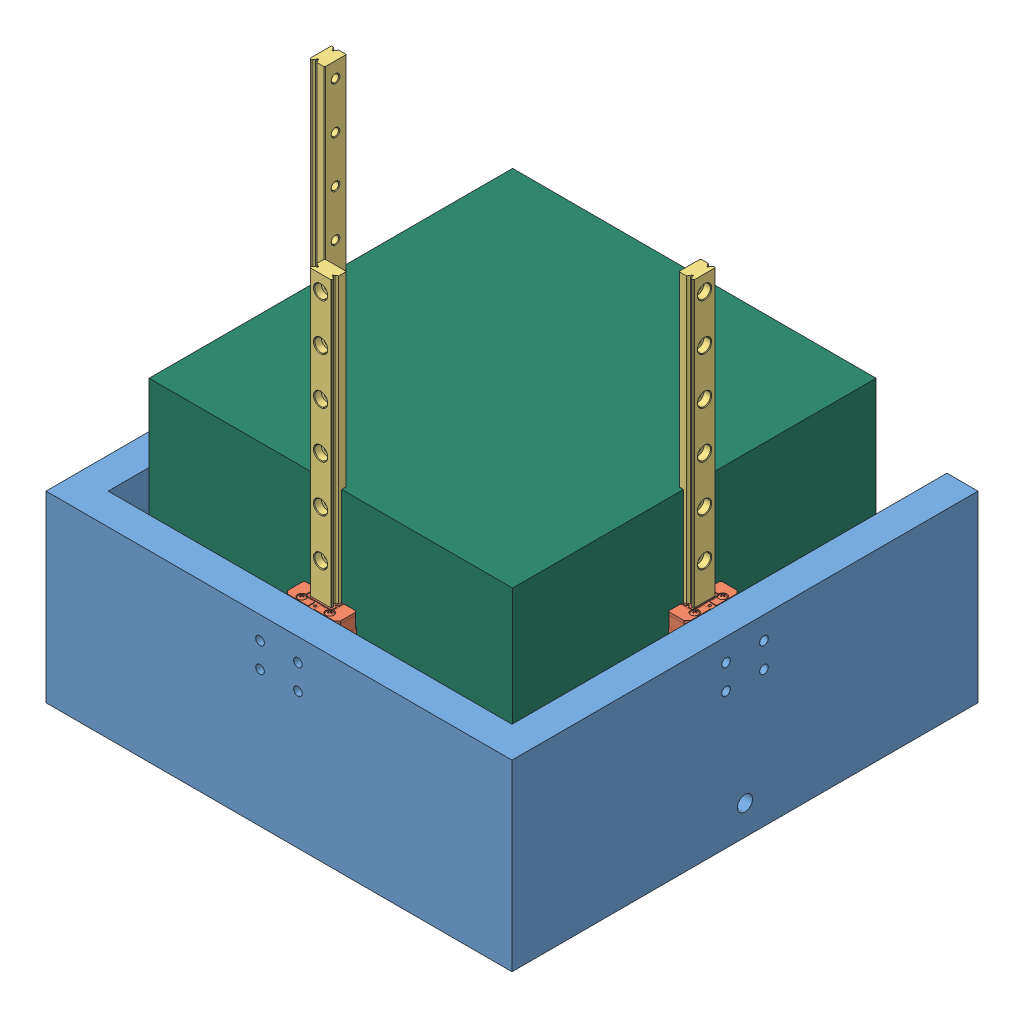
SolidWorks assembly faul_mntg_rig_assem, configuration Default. Lengths in mm.
Overall size (150 150.47 150).
44 component instances, 18 part files, 26 mates.
Components (placement in the parent):
- rails-1: rails [Default] at (23.4642 89.2869 124.8226) size (150 59 150)
- MGN7C-1: MGN7C [MGN7C] at (23.5642 78.0369 186.5726) x (1 0 0) z (0 -1 0) size (17 6.5 23.31)
- MGN7C-2: MGN7C [MGN7C] at (-38.2858 78.0369 124.9226) x (0 0 -1) z (0 1 0) size (17 6.5 23.31)
- MGN7C-3: MGN7C [MGN7C] at (85.2142 78.0369 124.7226) x (0 0 -1) z (0 -1 0) size (17 6.5 23.31)
- MGN7 rail-1: MGN7 rail [150 mm] at (23.5605 180.7565 184.1263) x (1 0 0) z (0 -1 0) size (7 4.8 100)
- MGN7 rail-2: MGN7 rail [150 mm] at (-35.8395 180.7565 124.7263) x (0 0 1) z (0 -1 0) size (7 4.8 100)
- MGN7 rail-3: MGN7 rail [150 mm] at (82.9605 180.7565 124.7263) x (0 0 -1) z (0 -1 0) size (7 4.8 100)
- base-1: base [Default] at (-21.4395 30.2869 169.7263) size (130 19 90)
- MRW_FLYWHEEL-1: MRW_FLYWHEEL [Default] at (23.5605 46.2869 124.7263) x (-0.994636 0 -0.103442) z (0 1 0) size (55 55 3)
- topmount_with_bracket-3: topmount_with_bracket [Default] at (-43.6188 119.1781 124.9527) x (1 0 0) z (0 -1 0) size (117 117 49.9)
  - MRW_MOUNTING_BRACKET-1: MRW_MOUNTING_BRACKET [Default] at (67.1793 -0.2264 38.4216) size (96 96 8)
  - MRW_MOTOR-1: MRW_MOTOR [Default] at (67.1793 -0.2264 43.3216) x (0 1 0) z (0 0 1) size (18.44 18.72 13.8)
  - MRW_RING-1: MRW_RING [Default] at (67.1793 -0.2264 40.4216) x (0 1 0) z (1 0 0) size (25 2 24.36)
  - M4_NUT-1: M4_NUT [91828A231] at (78.6793 -38.4764 42.0216) size (7 8.08 3.76)
  - M4_NUT-2: M4_NUT [91828A231] at (63.4393 -20.6964 42.0216) x (0.98295 -0.183873 0) z (0 0 1) size (7 8.08 3.76)
  - M4_STANDOFF-1: M4_STANDOFF [94868A033] at (78.6793 -38.4764 36.9216) x (-0.189466 -0.981887 0) z (0 0 1) size (6 6.93 3.46)
  - M4_STANDOFF-2: M4_STANDOFF [94868A033] at (63.4393 -20.6964 36.9216) x (0.997018 -0.077168 0) z (0 0 1) size (6 6.93 3.46)
  - M4_SCREW-1: M4_SCREW [91292A116] at (78.6793 -38.4764 43.9216) x (0.77219 -0.635391 0) z (0 0 1) size (7 7 14.32)
  - M4_SCREW-2: M4_SCREW [91292A116] at (63.4393 -20.6964 43.9216) x (0.958659 -0.284556 0) z (0 0 1) size (7 7 14.32)
  - M2_MRW_RING_SCREW-1: M2_MRW_RING_SCREW [97763A407] at (73.8993 -6.9464 37.1216) x (-0.944517 -0.328463 0) z (0 0 -1) size (3.5 3.5 7.52)
  - M2_MRW_RING_SCREW-2: M2_MRW_RING_SCREW [97763A407] at (57.1793 -0.2264 37.1216) x (-0.957584 -0.288153 0) z (0 0 -1) size (3.5 3.5 7.52)
  - M2_MRW_RING_SCREW-3: M2_MRW_RING_SCREW [97763A407] at (60.4593 6.4936 37.1216) x (-0.947368 -0.320145 0) z (0 0 -1) size (3.5 3.5 7.52)
  - M2_MRW_RING_SCREW-4: M2_MRW_RING_SCREW [97763A407] at (60.4593 -6.9464 37.1216) x (0.638032 0.77001 0) z (0 0 -1) size (3.5 3.5 7.52)
  - M2_MRW_RING_SCREW-5: M2_MRW_RING_SCREW [97763A407] at (67.1793 9.7736 37.1216) x (-0.93126 0.364355 0) z (0 0 -1) size (3.5 3.5 7.52)
  - M2_MRW_RING_SCREW-6: M2_MRW_RING_SCREW [97763A407] at (73.8993 6.4936 37.1216) x (-0.926006 -0.37751 0) z (0 0 -1) size (3.5 3.5 7.52)
  - M2_MRW_RING_SCREW-7: M2_MRW_RING_SCREW [97763A407] at (67.1793 -10.2264 37.1216) x (-0.936231 -0.351386 0) z (0 0 -1) size (3.5 3.5 7.52)
  - M2_NUT-1: M2_NUT [91828A111] at (57.1793 -0.2264 43.2216) x (0.997672 -0.068195 0) z (0 0 1) size (4 4.62 1.83)
  - M2_NUT-2: M2_NUT [91828A111] at (60.4593 6.4936 44.1216) x (0.99993 0.011815 0) z (0 0 1) size (4 4.62 1.83)
  - M2_NUT-3: M2_NUT [91828A111] at (73.8993 -6.9464 44.1216) size (4 4.62 1.83)
  - M2_NUT-4: M2_NUT [91828A111] at (67.1793 -10.2264 43.2216) x (0.930653 0.365904 0) z (0 0 1) size (4 4.62 1.83)
  - M2_NUT-5: M2_NUT [91828A111] at (60.4593 -6.9464 44.1216) x (0.997312 0.073269 0) z (0 0 1) size (4 4.62 1.83)
  - M2_NUT-6: M2_NUT [91828A111] at (73.8993 6.4936 44.1216) x (0.729203 -0.684297 0) z (0 0 1) size (4 4.62 1.83)
  - M2_NUT-7: M2_NUT [91828A111] at (67.1793 9.7736 43.2216) x (0.99281 0.119702 0) z (0 0 1) size (4 4.62 1.83)
  - M3_8mm_SCREW-2: M3_8mm_SCREW [91292A112] at (93.725 -26.4513 34.4216) x (0.980944 0.194292 0) z (0 0 -1) size (5.5 5.5 11.2) (hidden)
  - M3_8mm_SCREW-3: M3_8mm_SCREW [91292A112] at (40.907 -26.5626 34.4216) x (0.826921 -0.562317 0) z (0 0 -1) size (5.5 5.5 11.2) (hidden)
  - M3_8mm_SCREW-4: M3_8mm_SCREW [91292A112] at (40.5872 26.1503 34.4216) x (-0.613584 0.78963 0) z (0 0 -1) size (5.5 5.5 11.2) (hidden)
  - M3_8mm_SCREW-5: M3_8mm_SCREW [91292A112] at (93.6793 26.2736 34.4216) x (-1 0 0) z (0 0 -1) size (5.5 5.5 11.2) (hidden)
  - M3_NUT-1: M3_NUT [91828A211] at (93.725 -26.4513 37.2216) size (5.5 6.35 2.78) (hidden)
  - M3_NUT-2: M3_NUT [91828A211] at (93.6793 26.2736 37.2216) size (5.5 6.35 2.78) (hidden)
  - M3_NUT-3: M3_NUT [91828A211] at (40.5872 26.1503 37.2216) x (0.981625 0.190822 0) z (0 0 1) size (5.5 6.35 2.78) (hidden)
  - M3_NUT-4: M3_NUT [91828A211] at (40.907 -26.5626 37.2216) x (0.993227 -0.116192 0) z (0 0 1) size (5.5 6.35 2.78) (hidden)
  - MRW_PCB_FAKE-1: MRW_PCB_FAKE [Default] at (74.8693 -29.5864 33.9216) size (32 23 3)
  - MRW_LID-2: MRW_LID [Default] at (67.1793 -0.2264 40.4216) x (1 0 0) z (0 -1 0) size (61 12 61) (hidden)
  - topmount-1: topmount [Default] at (67.1793 -0.2264 -1.5784) x (0 -1 0) z (0 0 1) size (117 117 40)
Mates (geometry in assembly coordinates):
- Coincident1: coincident anti-aligned: plane of rails-1 through (-41.5358 30.2869 189.8226) normal (0 0 -1); plane of MGN7C-1 through (23.5642 71.2869 189.8226) normal (0 0 1)
- Coincident2: coincident anti-aligned: circle of rails-1; circle of MGN7C-1
- Parallel1: parallel aligned: line of rails-1 through (-41.5358 89.2869 189.8226) axis (1 0 0); line of MGN7C-1 through (24.5268 89.2869 189.6226) axis (1 0 0)
- Coincident6: coincident aligned: circle of rails-1; circle of MGN7C-2
- Parallel2: parallel anti-aligned: line of rails-1 through (-41.5358 89.2869 49.8226) axis (0 0 1); line of MGN7C-2 through (-41.3358 89.2869 123.9601) axis (0 0 -1)
- Coincident7: coincident anti-aligned: circle of rails-1; circle of MGN7C-3
- Parallel3: parallel aligned: line of rails-1 through (88.4642 89.2869 189.8226) axis (0 0 -1); line of MGN7C-3 through (88.2642 89.2869 132.2226) axis (0 0 -1)
- Coincident28: coincident anti-aligned: plane of MGN7C-3 through (85.2142 89.2869 122.3863) normal (0 0 1); plane of MGN7 rail-3 through (83.6105 80.7565 122.3863) normal (0 0 -1)
- Parallel5: parallel anti-aligned: plane of MGN7C-2 through (-38.2858 89.2869 127.259) normal (0 0 -1); plane of MGN7 rail-2 through (-36.4895 80.7565 127.0664) normal (0 0 1)
- Coincident50: coincident anti-aligned: plane of MGN7C-1 through (25.9006 89.2869 186.5726) normal (-1 0 0); plane of MGN7 rail-1 through (25.9006 80.7565 184.7763) normal (1 0 0)
- Parallel6: parallel anti-aligned: plane of MGN7C-2 through (-38.2858 89.2869 122.5863) normal (0 0 1); plane of MGN7 rail-2 through (-36.4895 80.7565 122.3863) normal (0 0 -1)
- Concentric2: concentric aligned: circle of base-1; circle of MRW_FLYWHEEL-1
- Coincident52: coincident anti-aligned: plane of base-1 through (23.5605 46.2869 124.7263) normal (0 1 0); plane of MRW_FLYWHEEL-1 through (23.5605 46.2869 124.7263) normal (0 -1 0)
- Coincident76: coincident anti-aligned: plane of MGN7 rail-3 through (80.5605 80.7565 128.0263) normal (-1 0 0); plane of topmount_with_bracket-3/topmount-1 through (80.5605 80.7565 128.2263) normal (1 0 0)
- Coincident77: coincident anti-aligned: plane of MGN7 rail-3 through (80.7605 80.7565 121.2263) normal (0 0 -1); plane of topmount_with_bracket-3/topmount-1 through (80.5605 80.7565 121.2263) normal (0 0 1)
- Coincident78: coincident anti-aligned: line of MGN7 rail-3 through (80.5605 80.7565 128.0263) axis (0 0 -1); line of topmount_with_bracket-3/topmount-1 through (80.5605 80.7565 121.2263) axis (0 0 1)
- Coincident81: coincident anti-aligned: plane of MGN7 rail-1 through (20.2605 80.7565 181.7263) normal (0 0 -1); plane of topmount_with_bracket-3/topmount-1 through (20.0605 80.7565 181.7263) normal (0 0 1)
- Coincident82: coincident anti-aligned: plane of MGN7 rail-1 through (27.0605 80.7565 181.9263) normal (1 0 0); plane of topmount_with_bracket-3/topmount-1 through (27.0605 80.7565 181.7263) normal (-1 0 0)
- Coincident83: coincident anti-aligned: line of MGN7 rail-1 through (20.2605 80.7565 181.7263) axis (1 0 0); line of topmount_with_bracket-3/topmount-1 through (27.0605 80.7565 181.7263) axis (-1 0 0)
- Coincident84: coincident anti-aligned: plane of MGN7 rail-2 through (-33.4395 80.7565 121.4263) normal (1 0 0); plane of topmount_with_bracket-3/topmount-1 through (-33.4395 80.7565 121.2263) normal (-1 0 0)
- Coincident85: coincident anti-aligned: plane of MGN7 rail-2 through (-33.6395 80.7565 128.2263) normal (0 0 1); plane of topmount_with_bracket-3/topmount-1 through (-33.4395 80.7565 128.2263) normal (0 0 -1)
- Coincident86: coincident anti-aligned: line of MGN7 rail-2 through (-33.4395 80.7565 121.4263) axis (0 0 1); line of topmount_with_bracket-3/topmount-1 through (-33.4395 80.7565 128.2263) axis (0 0 -1)
- Concentric8: concentric aligned: circle of MRW_FLYWHEEL-1; circle of topmount_with_bracket-3/MRW_MOTOR-1
- Parallel9: parallel anti-aligned: line of rails-1 through (-41.5358 30.2869 49.8226) axis (0 0 1); line of base-1 through (-41.4395 30.2869 146.7263) axis (0 0 -1)
- Parallel10: parallel aligned: line of rails-1 through (-41.5358 30.2869 189.8226) axis (1 0 0); line of base-1 through (1.5605 30.2869 169.7263) axis (1 0 0)
- Coincident97: coincident aligned: plane of rails-1 through (23.4642 30.2869 124.8226) normal (0 -1 0); plane of base-1 through (-21.4395 30.2869 169.7263) normal (0 -1 0)
